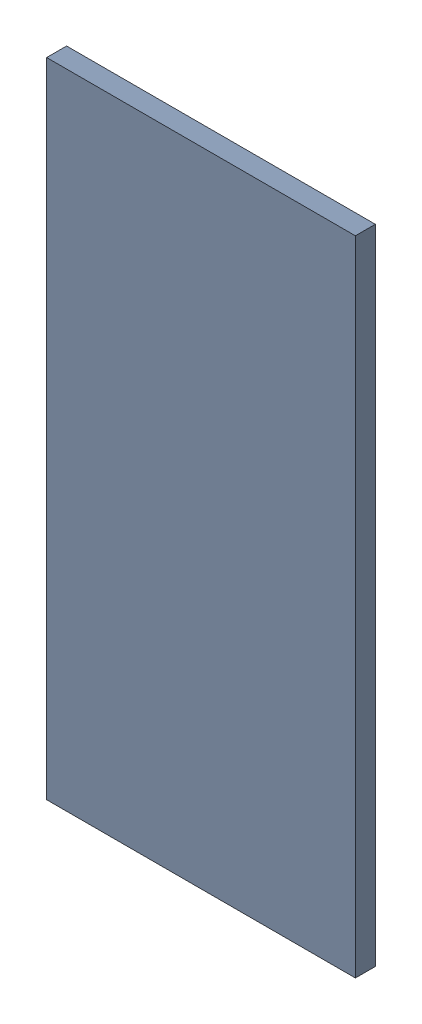
SolidWorks assembly Pad ADXL345-11(21.4mm,55.903mm) on Top Layer, configuration Predeterminado. Lengths in mm.
Overall size (0.55 1.15 0.04).
2 component instances, 1 part files, 0 mates.
Components (placement in the parent):
- Pad ADXL345-11(21.4mm,55.903mm) on Top Layer-1-1: Pad ADXL345-11(21.4mm,55.903mm) on Top Layer-1 [Predeterminado] at (-68.317 -44.187 -0.0457) size (0.55 1.15 0.04)
  - Pad ADXL345-11(21.4mm,55.903mm) on Top Layer-Part-1-1: Pad ADXL345-11(21.4mm,55.903mm) on Top Layer-Part-1 [Predeterminado] at origin size (0.55 1.15 0.04)
